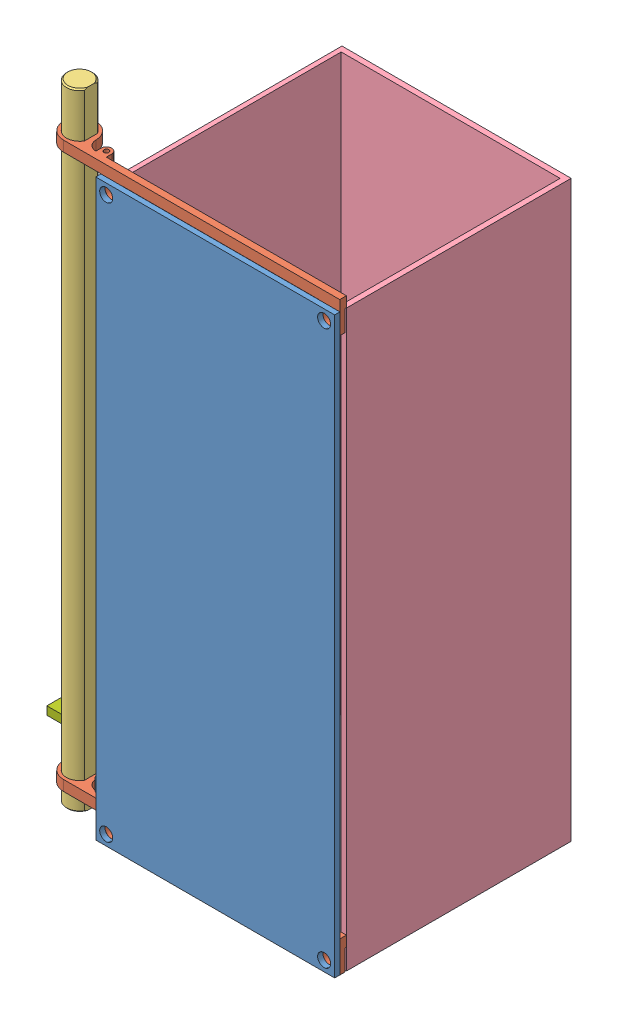
SolidWorks assembly Cylinder stacker final, configuration Default. Lengths in mm.
Overall size (90.77 164.64 57.51).
10 component instances, 8 part files, 13 mates.
Components (placement in the parent):
- window-1: window [Default] at (33.9342 142.3276 102.4553) x (0 -1 0) z (0 0 -1) size (139.72 58.13 1.27)
- door-1: door [Default] at (92.0314 142.3654 99.5695) x (-1 0 0) z (0 1 0) size (71.19 7.9 7.62)
- door-2: door [Default] at (92.0314 7.6488 99.5695) x (-1 0 0) z (0 1 0) size (71.19 7.9 7.62)
- 8632T132_D-Profile Rotary Shaft-1: 8632T132_D-Profile Rotary Shaft [8632T132] at (24.7951 79.6705 97.2364) x (0 0 -1) z (0 -1 0) size (6.35 6.35 152.4)
- silo-2: silo [Default] at (64.119 2.6629 72.9331) x (0 0 1) z (0 1 0) size (56.63 71.24 139.7)
- linkage-1: linkage [Default] at (32.061 12.7288 73.9152) x (-0.130417 0 0.991459) z (0 -1 0) size (26.65 3.92 2.54)
- Servohorn-1: Servohorn [Default] at (22.3115 12.7288 75.7336) x (1 0 0) z (0 1 0) size (18.2 6.8 3.8)
- SG-90-1: SG-90 [Predeterminado] at (21.9984 -40.7712 74.0932) size (32 26.5 12)
  - Pieza1-1: Pieza1 [Predeterminado] at (-4.6869 32 1.6404) size (32 21.5 12)
  - PZ2-1: PZ2 [Predeterminado] at (0.3131 58.5 1.6404) x (0.702574 0 -0.71161) z (0.71161 0 0.702574) size (4.99 10 4.99)
Mates (geometry in assembly coordinates):
- Concentric1: concentric aligned: cylinder of window-1 through (89.4914 139.8254 101.1853) axis (0 0 1) radius 1.5875; cylinder of door-1 through (89.4914 139.8254 99.9153) axis (0 0 1) radius 1.5875
- Coincident1: coincident anti-aligned: plane of window-1 through (33.9342 142.3276 101.1853) normal (0 0 -1); plane of door-1 through (92.0314 144.9054 101.1853) normal (0 0 1)
- Concentric3: concentric aligned: cylinder of window-1 through (89.4914 5.1088 101.1853) axis (0 0 1) radius 1.5875; cylinder of door-2 through (89.4914 5.1088 99.9153) axis (0 0 1) radius 1.5875
- Coincident2: coincident anti-aligned: plane of window-1 through (33.9342 142.3276 101.1853) normal (0 0 -1); plane of door-2 through (92.0314 10.1888 101.1853) normal (0 0 1)
- Concentric4: concentric anti-aligned: cylinder of door-2 through (24.7951 10.1888 97.2364) axis (0 -1 0) radius 3.175; cylinder of 8632T132_D-Profile Rotary Shaft-1 through (24.7951 3.4705 97.2364) axis (0 1 0) radius 3.175
- Parallel1: parallel anti-aligned: plane of door-2 through (27.5459 10.1888 99.5695) normal (-1 0 0); plane of 8632T132_D-Profile Rotary Shaft-1 through (27.5447 155.8705 98.8239) normal (1 0 0)
- Coincident4: coincident anti-aligned: circle of door-1; cylinder of 8632T132_D-Profile Rotary Shaft-1 through (24.7951 3.4705 97.2364) axis (0 1 0) radius 3.175
- Concentric5: concentric anti-aligned: cylinder of door-2 through (32.3471 10.1888 98.2694) axis (0 -1 0) radius 0.5994; cylinder of linkage-1 through (32.3471 10.1888 98.2694) axis (0 1 0) radius 0.5994
- Coincident6: coincident anti-aligned: plane of door-2 through (92.0314 10.1888 99.5695) normal (0 1 0); plane of linkage-1 through (35.3115 10.1888 75.7336) normal (0 -1 0)
- Concentric6: concentric anti-aligned: cylinder of linkage-1 through (35.3115 10.1888 75.7336) axis (0 1 0) radius 0.4978; cylinder of Servohorn-1 through (35.3115 16.5298 75.7336) axis (0 -1 0) radius 0.5
- Coincident7: coincident anti-aligned: plane of linkage-1 through (35.3115 12.7288 75.7336) normal (0 1 0); plane of Servohorn-1 through (35.3115 12.7288 75.7336) normal (0 -1 0)
- Concentric8: concentric aligned: cylinder of Servohorn-1 through (22.3115 6.082 75.7336) axis (0 1 0) radius 2.35; cylinder of SG-90-1/PZ2-1 through (22.3115 7.7288 75.7336) axis (0 1 0) radius 0.75
- Coincident8: coincident anti-aligned: plane of Servohorn-1 through (35.3115 12.7288 75.7336) normal (0 -1 0); plane of SG-90-1/Pieza1-1 through (22.3115 12.7288 75.7336) normal (0 1 0)
